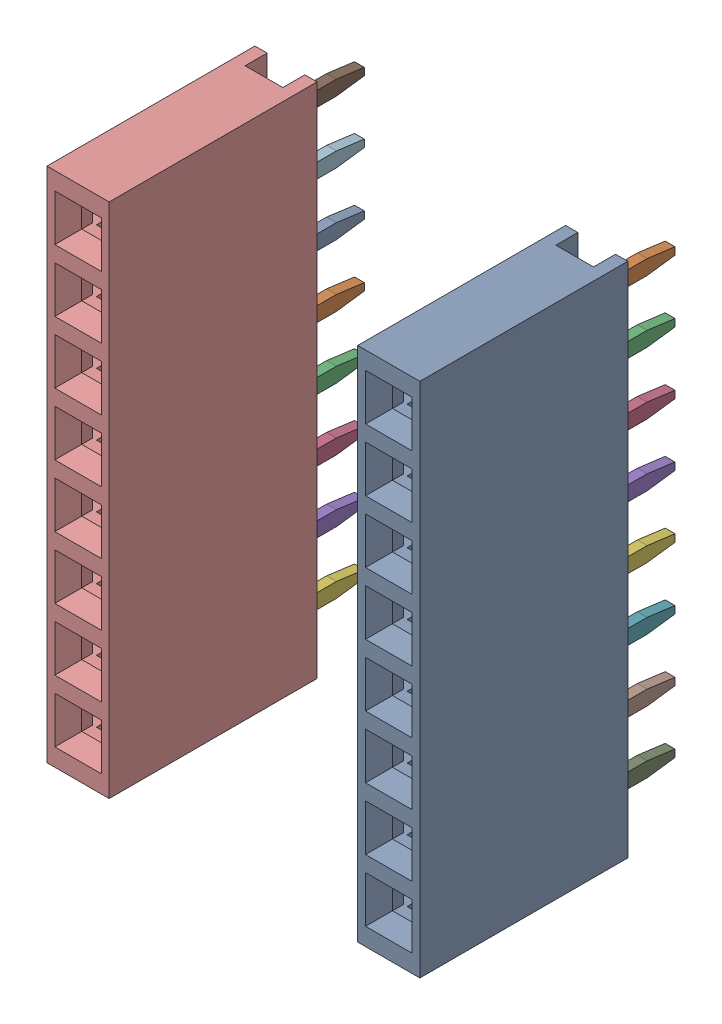
SolidWorks assembly X, configuration ﾃﾞﾌｫﾙﾄ. Lengths in mm.
Overall size (15.24 21.12 11.5).
2 component instances, 1 part files, 0 mates.
Components (placement in the parent):
- DS1023-1x8SF11-1: DS1023-1x8SF11 [ﾃﾞﾌｫﾙﾄ] at (13.9593 19.0061 0) x (0 -1 0) z (0 0 1) size (21.12 2.54 11.5)
- DS1023-1x8SF11-2: DS1023-1x8SF11 [ﾃﾞﾌｫﾙﾄ] at (1.2593 19.0061 0) x (0 -1 0) z (0 0 1) size (21.12 2.54 11.5)
